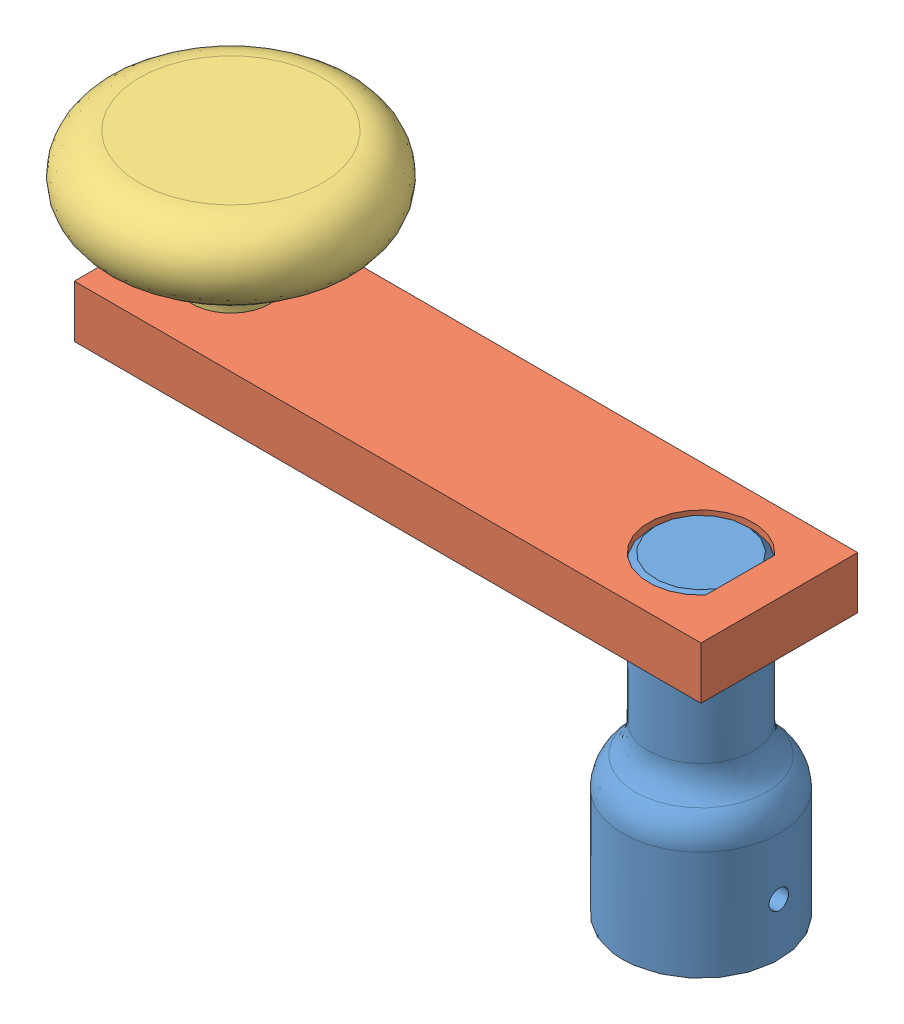
SolidWorks assembly crank-assy_&, configuration Default. Lengths in mm.
Overall size (89.08 53.98 44.81).
3 component instances, 3 part files, 8 mates.
Components (placement in the parent):
- crank-shaft_&-1: crank-shaft_& [Default] at origin size (19.05 38.1 19.05)
- crank-arm_&-1: crank-arm_& [Default] at (-66.675 31.75 -9.525) size (76.2 6.35 19.05)
- test-practicecrank-knob_&-1: test-practicecrank-knob_& [Default] at (-57.15 31.75 0) x (0.661436 0 -0.750001) z (0.750001 0 0.661436) size (31.75 22.23 31.75)
Mates (geometry in assembly coordinates):
- Coincident1: coincident aligned: plane of crank-shaft_&-1 through (0 0 0) normal (0 0 1); plane of assembly through (0 0 0) normal (0 0 1)
- Coincident2: coincident aligned: plane of crank-shaft_&-1 through (0 0 0) normal (0 1 0); plane of assembly through (0 0 0) normal (0 1 0)
- Coincident3: coincident aligned: plane of crank-shaft_&-1 through (0 0 0) normal (1 0 0); plane of assembly through (0 0 0) normal (1 0 0)
- Concentric1: concentric anti-aligned: cylinder of crank-shaft_&-1 through (0 38.1 0) axis (0 -1 0) radius 6.35; cylinder of crank-arm_&-1 through (0 31.75 0) axis (0 1 0) radius 6.35
- Parallel1: parallel anti-aligned: plane of crank-shaft_&-1 through (4.7625 31.75 4.2001) normal (1 0 0); plane of crank-arm_&-1 through (4.7625 31.75 -4.2001) normal (-1 0 0)
- Coincident4: coincident anti-aligned: plane of crank-shaft_&-1 through (0 31.75 0) normal (0 1 0); plane of crank-arm_&-1 through (-66.675 31.75 9.525) normal (0 -1 0)
- Concentric2: concentric anti-aligned: cylinder of crank-arm_&-1 through (-57.15 31.75 0) axis (0 1 0) radius 2.3813; cylinder of test-practicecrank-knob_&-1 through (-57.15 31.75 0) axis (0 -1 0) radius 2.3813
- Coincident5: coincident anti-aligned: plane of crank-arm_&-1 through (9.525 38.1 9.525) normal (0 1 0); plane of test-practicecrank-knob_&-1 through (-53.9999 38.1 -3.5719) normal (0 -1 0)
